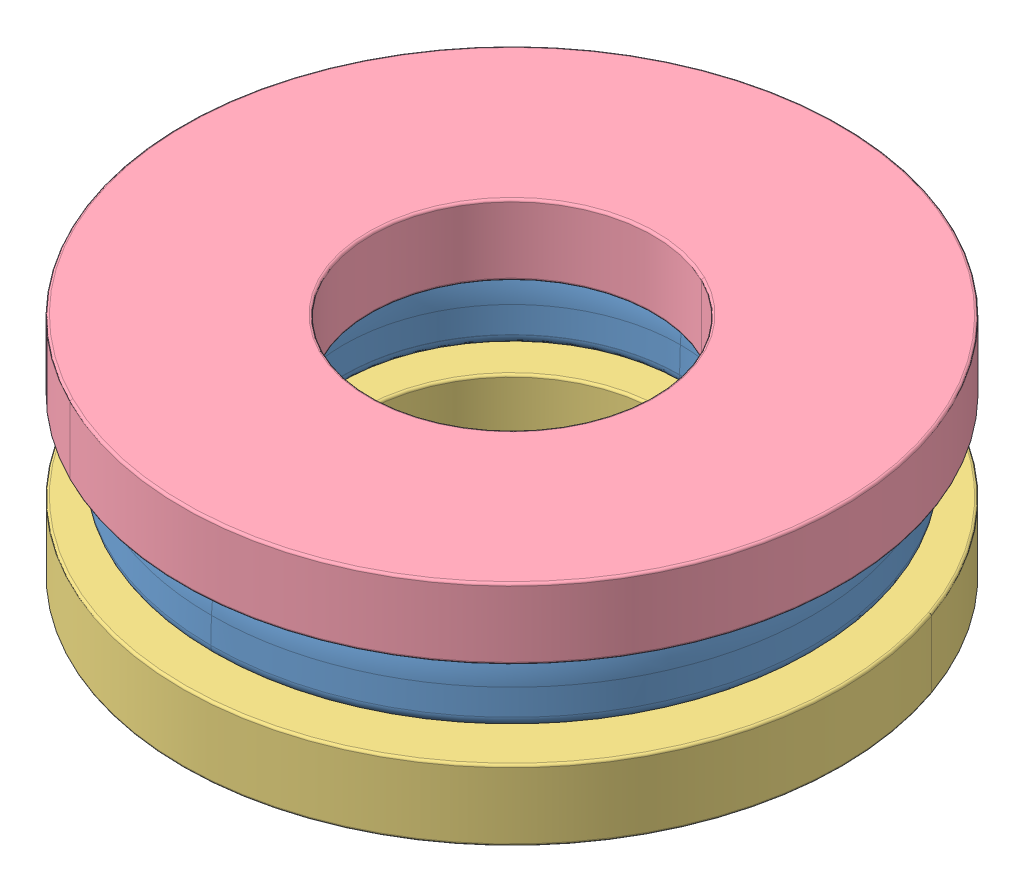
SolidWorks assembly 1613-0514-0006, configuration Default. Lengths in mm.
Overall size (18.78 4.84 18.78).
11 component instances, 4 part files, 0 mates.
Components (placement in the parent):
- 1613-0514-0006 carriage.STEP-1: 1613-0514-0006 carriage.STEP [Default] at (-24.6017 0.9565 11.8362) size (12.8 1.46 12.8)
- 1613-0514-0006 ball.STEP-1: 1613-0514-0006 ball.STEP [Default] at (-29.5231 1.6489 11.0748) size (2.37 2.37 2.37)
- 1613-0514-0006 ball.STEP-2: 1613-0514-0006 ball.STEP [Default] at (-27.5433 1.6489 7.8178) x (0.707107 0 0.707107) z (-0.707107 0 0.707107) size (2.37 2.37 2.37)
- 1613-0514-0006 ball.STEP-3: 1613-0514-0006 ball.STEP [Default] at (-23.8403 1.6489 6.9147) x (0 0 1) z (-1 0 0) size (2.37 2.37 2.37)
- 1613-0514-0006 ball.STEP-4: 1613-0514-0006 ball.STEP [Default] at (-20.5833 1.6489 8.8946) x (-0.707107 0 0.707107) z (-0.707107 0 -0.707107) size (2.37 2.37 2.37)
- 1613-0514-0006 ball.STEP-5: 1613-0514-0006 ball.STEP [Default] at (-19.6802 1.6489 12.5976) x (-1 0 0) z (0 0 -1) size (2.37 2.37 2.37)
- 1613-0514-0006 ball.STEP-6: 1613-0514-0006 ball.STEP [Default] at (-21.6601 1.6489 15.8546) x (-0.707107 0 -0.707107) z (0.707107 0 -0.707107) size (2.37 2.37 2.37)
- 1613-0514-0006 ball.STEP-7: 1613-0514-0006 ball.STEP [Default] at (-25.3631 1.6489 16.7576) x (0 0 -1) z (1 0 0) size (2.37 2.37 2.37)
- 1613-0514-0006 ball.STEP-8: 1613-0514-0006 ball.STEP [Default] at (-28.62 1.6489 14.7778) x (0.707107 0 -0.707107) z (0.707107 0 0.707107) size (2.37 2.37 2.37)
- 1613-0514-0006 washer (6.33mm ID).STEP-1: 1613-0514-0006 washer (6.33mm ID).STEP [Default] at (-24.6017 -0.7711 11.8362) x (0.328148 0 0.944626) z (-0.944626 0 0.328148) size (14 1.5 14)
- 1613-0514-0006 washer (6mm ID).STEP-1: 1613-0514-0006 washer (6mm ID).STEP [Default] at (-24.6017 4.0689 11.8362) x (-0.894397 0 -0.447274) z (-0.447274 0 0.894397) size (14 1.5 14)
